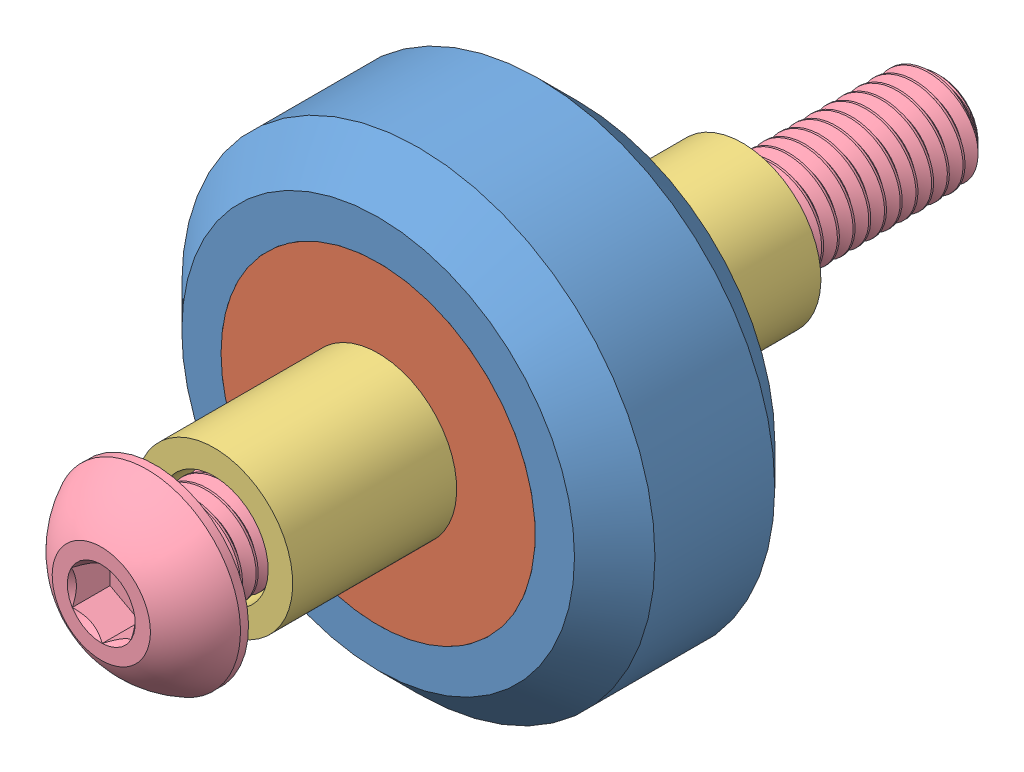
SolidWorks assembly Longer screw assembly, configuration Default. Lengths in mm.
Overall size (24.1 24.1 43.38).
6 component instances, 4 part files, 8 mates.
Components (placement in the parent):
- roller_rubber-1: roller_rubber [Default] at (5.0143 12.5185 20.6394) size (24.1 24.1 10.2)
- Bearing for Roller-1: Bearing for Roller [Default] at (5.0143 12.5185 15.5394) size (16 16 2)
- Bearing for Roller-2: Bearing for Roller [Default] at (5.0143 12.5185 23.7394) size (16 16 2)
- Roller Spacer-3: Roller Spacer [Default] at (5.0143 12.5185 25.7394) x (-0.5689 0.822407 0) z (0 0 1) size (8 8 8.35)
- Roller Spacer-4: Roller Spacer [Default] at (5.0143 12.5185 7.1894) x (-0.029804 -0.999556 0) z (0 0 1) size (8 8 8.35)
- 92095A222_Button Head Hex Drive Screw-1: 92095A222_Button Head Hex Drive Screw [92095A222] at (5.0143 12.5185 39.8394) x (0.476595 0.879123 0) z (0 0 1) size (9.5 9.5 43.38)
Mates (geometry in assembly coordinates):
- Coincident1: coincident aligned: circle of roller_rubber-1; circle of Bearing for Roller-2
- Coincident2: coincident aligned: circle of roller_rubber-1; circle of Bearing for Roller-1
- Coincident7: coincident anti-aligned: plane of Bearing for Roller-2 through (5.0143 12.5185 25.7394) normal (0 0 1); plane of Roller Spacer-3 through (5.0143 12.5185 25.7394) normal (0 0 -1)
- Concentric4: concentric aligned: circle of Bearing for Roller-2; circle of Roller Spacer-3
- Concentric5: concentric aligned: circle of Bearing for Roller-1; circle of Roller Spacer-4
- Coincident8: coincident anti-aligned: plane of Bearing for Roller-1 through (5.0143 12.5185 15.5394) normal (0 0 -1); plane of Roller Spacer-4 through (5.0143 12.5185 15.5394) normal (0 0 1)
- Concentric7: concentric aligned: circle of Roller Spacer-3; circle of 92095A222_Button Head Hex Drive Screw-1
- Distance2: distance = 3 mm anti-aligned: plane of Roller Spacer-3 through (5.0143 12.5185 34.0894) normal (0 0 1); plane of 92095A222_Button Head Hex Drive Screw-1 through (7.2782 16.6943 37.0894) normal (0 0 -1)
